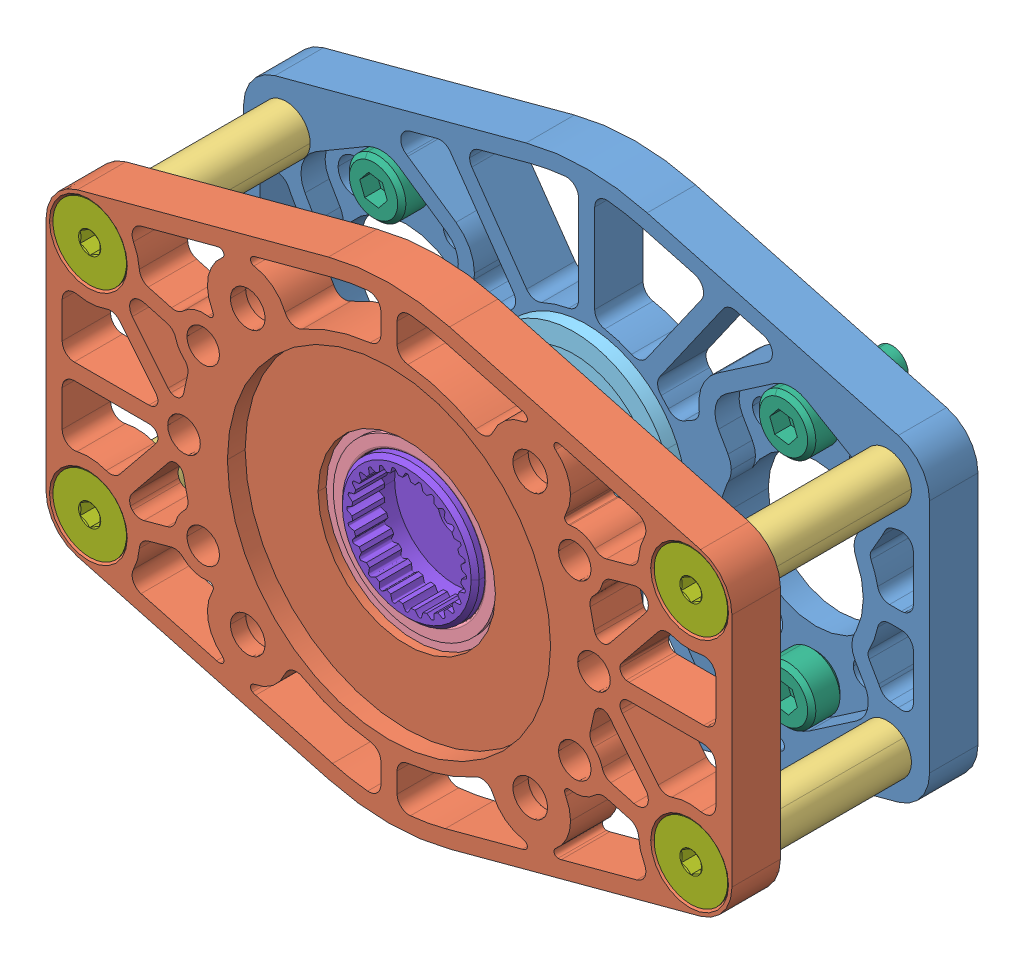
SolidWorks assembly doubleMotorVP, configuration Default. Lengths in mm.
Overall size (85 58 37.49).
18 component instances, 8 part files, 0 mates.
Components (placement in the parent):
- VersaDM_Gearbox_Aluminum_with_775pros_shown_217-6417(2)^doubleMotorVP-1: VersaDM_Gearbox_Aluminum_with_775pros_shown_217-6417(2)^doubleMotorVP [Default] at origin size (85 58 37.49) (virtual)
  - 217-6342-101 Rev4^VersaDM_Gearbox_Aluminum_with_775pros_shown_217-6417(2)_doubleMotorVP-1: 217-6342-101 Rev4^VersaDM_Gearbox_Aluminum_with_775pros_shown_217-6417(2)_doubleMotorVP [Default] at (0 0 -22.2875) size (85 58 6) (virtual)
  - 217-6342-102 Rev5^VersaDM_Gearbox_Aluminum_with_775pros_shown_217-6417(2)_doubleMotorVP-1: 217-6342-102 Rev5^VersaDM_Gearbox_Aluminum_with_775pros_shown_217-6417(2)_doubleMotorVP [Default] at (0 0 2.2) x (-1 0 0) z (0 0 -1) size (85 58 6) (virtual)
  - 217-6342-103 Rev3^VersaDM_Gearbox_Aluminum_with_775pros_shown_217-6417(2)_doubleMotorVP-1: 217-6342-103 Rev3^VersaDM_Gearbox_Aluminum_with_775pros_shown_217-6417(2)_doubleMotorVP [Default] at (37.25 -14.6067 -19.2875) x (0.682458 0.730925 0) z (0 0 1) size (6 6 18.49) (virtual)
  - 217-6342-103 Rev3^VersaDM_Gearbox_Aluminum_with_775pros_shown_217-6417(2)_doubleMotorVP-2: 217-6342-103 Rev3^VersaDM_Gearbox_Aluminum_with_775pros_shown_217-6417(2)_doubleMotorVP [Default] at (37.25 14.6067 -19.2875) x (0.998764 0.049702 0) z (0 0 1) size (6 6 18.49) (virtual)
  - 217-6342-103 Rev3^VersaDM_Gearbox_Aluminum_with_775pros_shown_217-6417(2)_doubleMotorVP-3: 217-6342-103 Rev3^VersaDM_Gearbox_Aluminum_with_775pros_shown_217-6417(2)_doubleMotorVP [Default] at (-37.25 -14.6067 -19.2875) size (6 6 18.49) (virtual)
  - 217-6342-103 Rev3^VersaDM_Gearbox_Aluminum_with_775pros_shown_217-6417(2)_doubleMotorVP-4: 217-6342-103 Rev3^VersaDM_Gearbox_Aluminum_with_775pros_shown_217-6417(2)_doubleMotorVP [Default] at (-37.25 14.6067 -19.2875) size (6 6 18.49) (virtual)
  - 217-2741-001 Rev4^VersaDM_Gearbox_Aluminum_with_775pros_shown_217-6417(2)_doubleMotorVP-1: 217-2741-001 Rev4^VersaDM_Gearbox_Aluminum_with_775pros_shown_217-6417(2)_doubleMotorVP [Default] at (0 0 -3) x (0 0 1) z (-0.18806 -0.982158 0) size (5 26 26) (virtual)
  - 217-2733-001 Rev4^VersaDM_Gearbox_Aluminum_with_775pros_shown_217-6417(2)_doubleMotorVP-1: 217-2733-001 Rev4^VersaDM_Gearbox_Aluminum_with_775pros_shown_217-6417(2)_doubleMotorVP [Default] at (0 0 -17.7) x (0 0 -1) z (0.909408 0.415905 0) size (7.11 24.61 24.61) (virtual)
  - 217-4649-006 Rev1_SSA0004-008BA^VersaDM_Gearbox_Aluminum_with_775pros_shown_217-6417(2)_doubleMotorVP-1: 217-4649-006 Rev1_SSA0004-008BA^VersaDM_Gearbox_Aluminum_with_775pros_shown_217-6417(2)_doubleMotorVP [Default] at (-25.4 14.5 -22.2875) x (0.934584 0.355742 0) z (0.355742 -0.934584 0) size (7 14 7) (virtual)
  - 217-4649-006 Rev1_SSA0004-008BA^VersaDM_Gearbox_Aluminum_with_775pros_shown_217-6417(2)_doubleMotorVP-2: 217-4649-006 Rev1_SSA0004-008BA^VersaDM_Gearbox_Aluminum_with_775pros_shown_217-6417(2)_doubleMotorVP [Default] at (25.4 14.5 -22.2875) x (-0.932211 -0.361914 0) z (-0.361914 0.932211 0) size (7 14 7) (virtual)
  - #8-32 FHCS, Grade 8 Steel Rev1_SFA0832-1125ZB^VersaDM_Gearbox_Aluminum_with_775pros_shown_217-6417(2)_doubleMotorVP-1: #8-32 FHCS, Grade 8 Steel Rev1_SFA0832-1125ZB^VersaDM_Gearbox_Aluminum_with_775pros_shown_217-6417(2)_doubleMotorVP [Default] at (37.25 -14.6067 5.0367) size (9.12 9.12 28.58) (virtual)
  - #8-32 FHCS, Grade 8 Steel Rev1_SFA0832-1125ZB^VersaDM_Gearbox_Aluminum_with_775pros_shown_217-6417(2)_doubleMotorVP-2: #8-32 FHCS, Grade 8 Steel Rev1_SFA0832-1125ZB^VersaDM_Gearbox_Aluminum_with_775pros_shown_217-6417(2)_doubleMotorVP [Default] at (-37.25 14.6067 5.0367) size (9.12 9.12 28.58) (virtual)
  - #8-32 FHCS, Grade 8 Steel Rev1_SFA0832-1125ZB^VersaDM_Gearbox_Aluminum_with_775pros_shown_217-6417(2)_doubleMotorVP-3: #8-32 FHCS, Grade 8 Steel Rev1_SFA0832-1125ZB^VersaDM_Gearbox_Aluminum_with_775pros_shown_217-6417(2)_doubleMotorVP [Default] at (-37.25 -14.6067 5.0367) size (9.12 9.12 28.58) (virtual)
  - #8-32 FHCS, Grade 8 Steel Rev1_SFA0832-1125ZB^VersaDM_Gearbox_Aluminum_with_775pros_shown_217-6417(2)_doubleMotorVP-4: #8-32 FHCS, Grade 8 Steel Rev1_SFA0832-1125ZB^VersaDM_Gearbox_Aluminum_with_775pros_shown_217-6417(2)_doubleMotorVP [Default] at (37.25 14.6067 5.0367) size (9.12 9.12 28.58) (virtual)
  - 217-6342-009 Rev3^VersaDM_Gearbox_Aluminum_with_775pros_shown_217-6417(2)_doubleMotorVP-1: 217-6342-009 Rev3^VersaDM_Gearbox_Aluminum_with_775pros_shown_217-6417(2)_doubleMotorVP [Default] at origin size (18 18 27.86) (virtual)
  - 217-4649-006 Rev1_SSA0004-008BA^VersaDM_Gearbox_Aluminum_with_775pros_shown_217-6417(2)_doubleMotorVP-3: 217-4649-006 Rev1_SSA0004-008BA^VersaDM_Gearbox_Aluminum_with_775pros_shown_217-6417(2)_doubleMotorVP [Default] at (25.4 -14.5 -22.2875) x (0.932211 0.361914 0) z (0.361914 -0.932211 0) size (7 14 7) (virtual)
  - 217-4649-006 Rev1_SSA0004-008BA^VersaDM_Gearbox_Aluminum_with_775pros_shown_217-6417(2)_doubleMotorVP-4: 217-4649-006 Rev1_SSA0004-008BA^VersaDM_Gearbox_Aluminum_with_775pros_shown_217-6417(2)_doubleMotorVP [Default] at (-25.4 -14.5 -22.2875) x (-0.934584 -0.355742 0) z (-0.355742 0.934584 0) size (7 14 7) (virtual)
